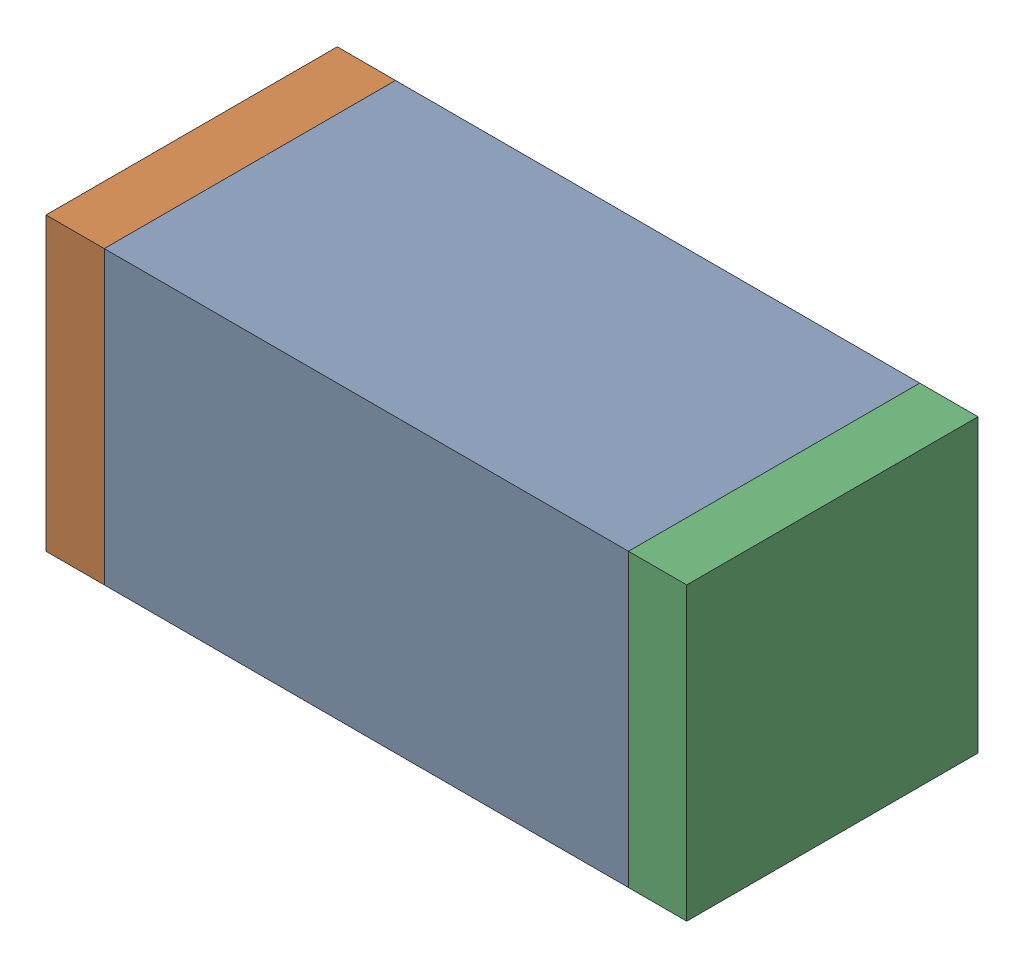
SolidWorks assembly C86, configuration Default. Lengths in mm.
Overall size (1.1 0.5 0.5).
6 component instances, 2 part files, 0 mates.
Components (placement in the parent):
- 836749680-1: 836749680 [Default] at (130.05 64 0) size (0.9 0.5 0.5)
  - Extruded_4-1: Extruded_4 [Default] at origin size (0.9 0.5 0.5)
- 810156080-1: 810156080 [Default] at (129.55 64 0) size (0.1 0.5 0.5)
  - Extruded_5-1: Extruded_5 [Default] at origin size (0.1 0.5 0.5)
- 810156080-2: 810156080 [Default] at (130.55 64 0) size (0.1 0.5 0.5)
  - Extruded_5-1: Extruded_5 [Default] at origin size (0.1 0.5 0.5)
